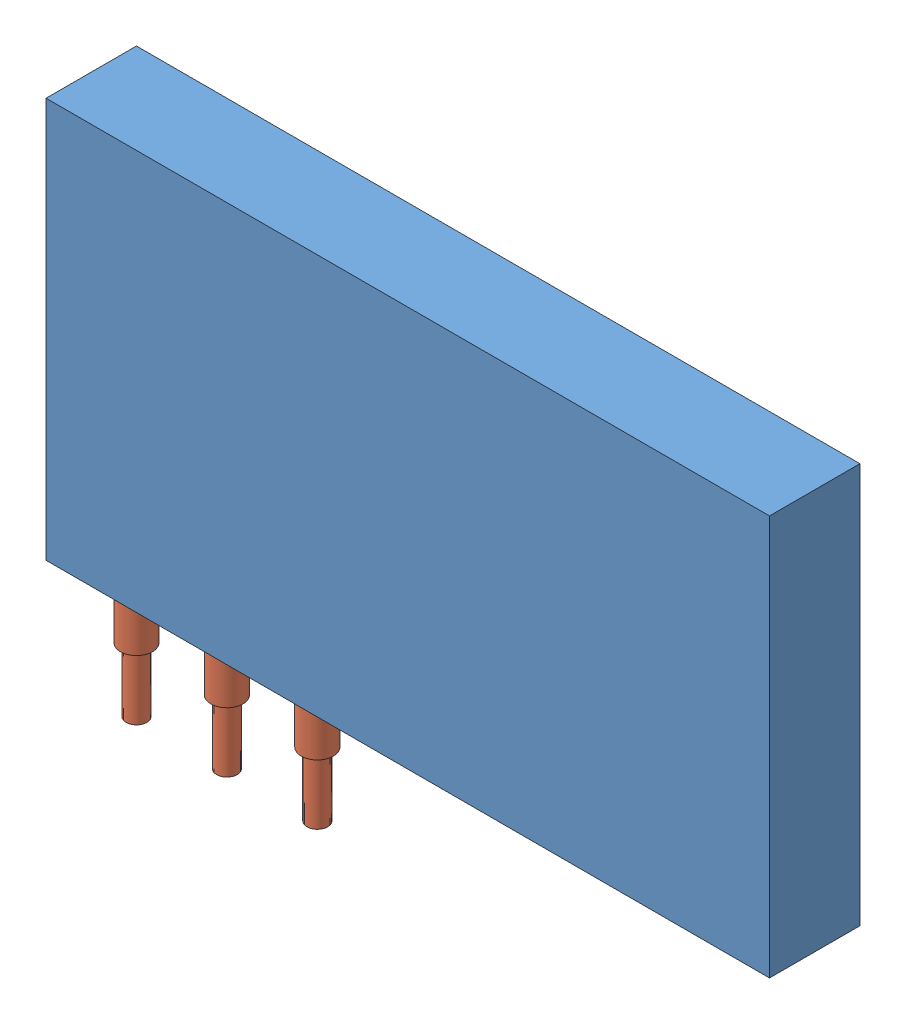
SolidWorks assembly brass collet fitting and aluminum tube connector_cut out of aluminum stock, configuration Default. Lengths in mm.
Overall size (101.6 75.2 12.7).
4 component instances, 2 part files, 6 mates.
Components (placement in the parent):
- Aluminum stock-1: Aluminum stock [Default] at (85.3034 25.0463 77.96) size (101.6 56.2 12.7)
- brass collet fitting and aluminum tube connector-1: brass collet fitting and aluminum tube connector [Default] at (-9.9466 15.0463 72.9126) x (-0.837169 0 -0.546944) z (0 1 0) size (7.95 7.95 19)
- brass collet fitting and aluminum tube connector-2: brass collet fitting and aluminum tube connector [Default] at (2.7534 15.0463 72.9126) x (0.556807 0 -0.830642) z (0 1 0) size (7.95 7.95 19)
- brass collet fitting and aluminum tube connector-3: brass collet fitting and aluminum tube connector [Default] at (15.4534 15.0463 72.9126) x (0.70889 0 -0.705319) z (0 1 0) size (7.95 7.95 19)
Mates (geometry in assembly coordinates):
- Coincident1: coincident anti-aligned: plane of Aluminum stock-1 through (85.3034 25.0463 77.96) normal (0 -1 0); plane of brass collet fitting and aluminum tube connector-1 through (-9.9466 25.0463 72.9126) normal (0 1 0)
- Coincident6: coincident: point of Aluminum stock-1; point of brass collet fitting and aluminum tube connector-1
- Coincident8: coincident anti-aligned: plane of Aluminum stock-1 through (85.3034 25.0463 77.96) normal (0 -1 0); plane of brass collet fitting and aluminum tube connector-2 through (2.7534 25.0463 72.9126) normal (0 1 0)
- Coincident9: coincident: point of Aluminum stock-1; point of brass collet fitting and aluminum tube connector-2
- Coincident10: coincident anti-aligned: plane of Aluminum stock-1 through (85.3034 25.0463 77.96) normal (0 -1 0); plane of brass collet fitting and aluminum tube connector-3 through (15.4534 25.0463 72.9126) normal (0 1 0)
- Coincident11: coincident: point of Aluminum stock-1; point of brass collet fitting and aluminum tube connector-3
